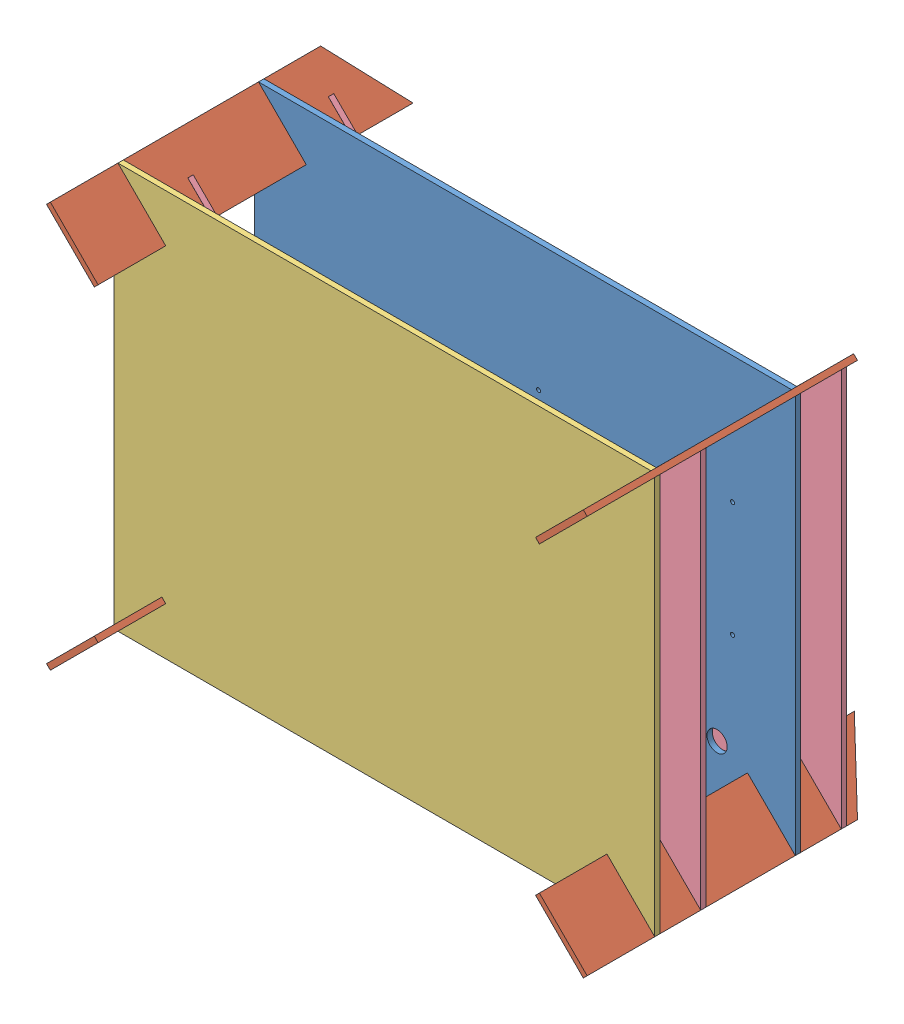
SolidWorks assembly Assemblage1, configuration Défaut. Lengths in mm.
Overall size (400 300 233).
8 component instances, 4 part files, 20 mates.
Components (placement in the parent):
- plaque plaque base-4: plaque plaque base [Défaut] at (233.5981 15.7105 0) size (400 300 4)
- pieds latéraux-2: pieds latéraux [Défaut] at (-132.4307 51.3763 95.6822) x (0.707107 -0.707107 0) z (0.707107 0.707107 0) size (50 233 4)
- plaque xbox-1: plaque xbox [Défaut] at (224.8548 3.6116 104) size (400 300 4)
- pieds latéraux-3: pieds latéraux [Défaut] at (103.4288 54.2047 95.6822) x (-0.707107 -0.707107 0) z (0.707107 -0.707107 0) size (50 233 4)
- pieds latéraux-4: pieds latéraux [Défaut] at (106.2573 -81.6548 95.6822) x (-0.707107 0.707107 0) z (-0.707107 -0.707107 0) size (50 233 4)
- pieds latéraux-5: pieds latéraux [Défaut] at (-129.6022 -84.4832 95.6822) x (0.707107 0.707107 0) z (-0.707107 0.707107 0) size (50 233 4)
- rambarde-1: rambarde [Défaut] at (221.0727 7.3937 70) size (400 297.17 4)
- rambarde-2: rambarde [Défaut] at (221.0727 7.3937 -34) size (400 297.17 4)
Mates (geometry in assembly coordinates):
- Coïncidente1: coincident anti-aligned: plane of plaque plaque base-4 through (-192.5806 117.1831 4) normal (-0.707107 0.707107 0); plane of pieds latéraux-2 through (-192.5806 117.1831 108) normal (0.707107 -0.707107 0)
- Coïncidente2: coincident aligned: line of plaque plaque base-4 through (-192.5806 117.1831 4) axis (0 0 -1); line of pieds latéraux-2 through (-192.5806 117.1831 108) axis (0 0 -1)
- Coïncidente6: coincident anti-aligned: plane of plaque plaque base-4 through (-192.5806 117.1831 0) normal (0 0 -1); plane of pieds latéraux-2 through (-192.5806 117.1831 0) normal (0 0 1)
- Coïncidente11: coincident aligned: line of pieds latéraux-2 through (-192.5806 117.1831 104) axis (0.707107 -0.707107 0); line of plaque xbox-1 through (-210.2583 134.8608 104) axis (0.707107 -0.707107 0)
- Coïncidente15: coincident anti-aligned: plane of pieds latéraux-2 through (-192.5806 117.1831 108) normal (0.707107 -0.707107 0); plane of plaque xbox-1 through (-192.5806 117.1831 108) normal (-0.707107 0.707107 0)
- Perpendiculaire1: perpendicular: plane of pieds latéraux-2 through (-210.2583 134.8608 -42) normal (0.707107 0.707107 0); plane of plaque xbox-1 through (-192.5806 117.1831 104) normal (0 0 -1)
- Coïncidente23: coincident aligned: line of plaque plaque base-4 through (169.2356 114.3547 4) axis (0 0 -1); line of pieds latéraux-3 through (169.2356 114.3547 4) axis (0 0 -1)
- Coïncidente25: coincident aligned: line of plaque plaque base-4 through (186.9133 132.0323 0) axis (-0.707107 -0.707107 0); line of pieds latéraux-3 through (169.2356 114.3547 0) axis (-0.707107 -0.707107 0)
- Parallèle1: parallel anti-aligned: line of plaque plaque base-4 through (169.2356 -144.6331 0) axis (0.707107 -0.707107 0); line of pieds latéraux-4 through (169.2356 -144.6331 0) axis (-0.707107 0.707107 0)
- Coïncidente37: coincident aligned: line of plaque plaque base-4 through (184.0849 -165.1392 0) axis (-0.707107 0.707107 0); line of pieds latéraux-4 through (166.4072 -147.4616 0) axis (-0.707107 0.707107 0)
- Coïncidente41: coincident aligned: line of plaque xbox-1 through (166.4072 -147.4616 104) axis (0.707107 0.707107 0); line of pieds latéraux-4 through (166.4072 -147.4616 104) axis (0.707107 0.707107 0)
- Parallèle3: parallel anti-aligned: line of plaque plaque base-4 through (-192.5806 -147.4616 0) axis (-0.707107 -0.707107 0); line of pieds latéraux-5 through (-192.5806 -147.4616 0) axis (0.707107 0.707107 0)
- Coïncidente43: coincident anti-aligned: line of plaque plaque base-4 through (-192.5806 -147.4616 0) axis (-0.707107 -0.707107 0); line of pieds latéraux-5 through (-192.5806 -147.4616 0) axis (0.707107 0.707107 0)
- Coïncidente44: coincident aligned: line of plaque xbox-1 through (-195.409 -144.6331 108) axis (0.707107 -0.707107 0); line of pieds latéraux-5 through (-195.409 -144.6331 108) axis (0.707107 -0.707107 0)
- Coïncidente45: coincident anti-aligned: plane of pieds latéraux-4 through (166.4072 -147.4616 74) normal (-0.707107 0.707107 0); plane of rambarde-1 through (169.2356 -144.6331 74) normal (0.707107 -0.707107 0)
- Coïncidente46: coincident aligned: line of pieds latéraux-4 through (151.558 -126.9555 74) axis (0.707107 -0.707107 0); line of rambarde-1 through (169.2356 -144.6331 74) axis (0.707107 -0.707107 0)
- Coïncidente47: coincident anti-aligned: line of pieds latéraux-5 through (-177.7314 -126.9555 74) axis (-0.707107 -0.707107 0); line of rambarde-1 through (-213.0867 -162.3108 74) axis (0.707107 0.707107 0)
- Coïncidente48: coincident anti-aligned: plane of pieds latéraux-4 through (166.4072 -147.4616 -30) normal (-0.707107 0.707107 0); plane of rambarde-2 through (169.2356 -144.6331 -30) normal (0.707107 -0.707107 0)
- Coïncidente49: coincident anti-aligned: line of pieds latéraux-4 through (148.7295 -129.7839 -30) axis (0.707107 -0.707107 0); line of rambarde-2 through (184.0849 -165.1392 -30) axis (-0.707107 0.707107 0)
- Coïncidente50: coincident anti-aligned: line of pieds latéraux-5 through (-177.7314 -126.9555 -30) axis (-0.707107 -0.707107 0); line of rambarde-2 through (-213.0867 -162.3108 -30) axis (0.707107 0.707107 0)
